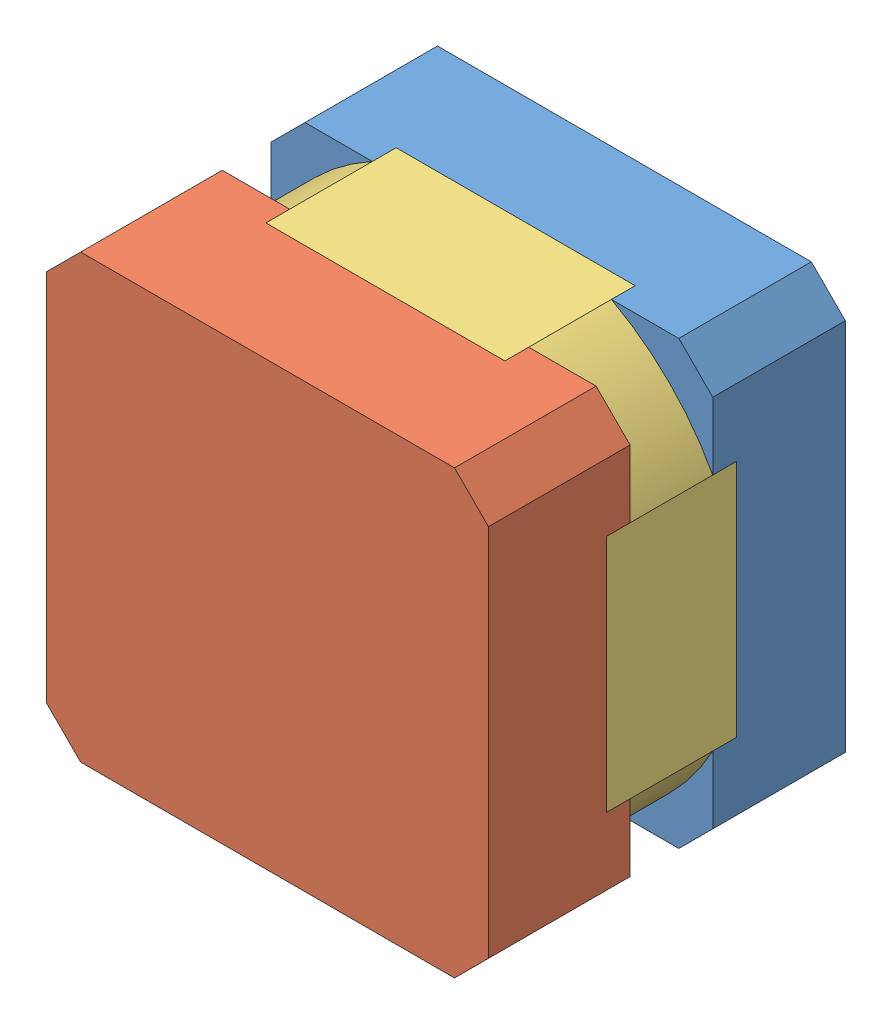
SolidWorks assembly Motor NEMA 16, configuration Valor predeterminado. Lengths in mm.
Overall size (39 39 47.5).
4 component instances, 4 part files, 12 mates.
Components (placement in the parent):
- Flange Dianteira^Motor NEMA 16-1: Flange Dianteira^Motor NEMA 16 [Valor predeterminado] at origin size (39 39 11.7) (virtual)
- Flange Traseira^Motor NEMA 16-1: Flange Traseira^Motor NEMA 16 [Valor predeterminado] at (0 0 31.5) x (-1 0 0) z (0 0 -1) size (39 39 12.5) (virtual)
- Núcleo^Motor NEMA 16-2: Núcleo^Motor NEMA 16 [Valor predeterminado] at (0 0 21.1) x (-1 0 0) z (0 0 -1) size (39 39 11.5) (virtual)
- Peça3^Motor NEMA 16-1: Peça3^Motor NEMA 16 [Valor predeterminado] at (93.2899 3.2981 -16) x (-0.956559 0.291538 0) z (0 0 1) size (5 5 16) (virtual)
Mates (geometry in assembly coordinates):
- No local1: in place: plane of Flange Dianteira^Motor NEMA 16-1 through (0 0 0) normal (0 0 1); moOrthogonalPlaneRef_w of Flange Dianteira^Motor NEMA 16-1 through (0 0 0) normal (0 1 0); plane of Flange Dianteira^Motor NEMA 16-1 through (0 0 0) normal (1 0 0); unknown of Flange Dianteira^Motor NEMA 16-1
- Coincidente1: coincident aligned: plane of Flange Dianteira^Motor NEMA 16-1; plane of assembly
- Coincidente2: coincident aligned: plane of Flange Dianteira^Motor NEMA 16-1 through (0 0 0) normal (0 1 0); moOrthogonalPlaneRef_w of assembly
- Coincidente3: coincident anti-aligned: plane of Flange Dianteira^Motor NEMA 16-1 through (0 0 0) normal (1 0 0); moOrthogonalPlaneRef_w of assembly
- Coincidente7: coincident anti-aligned: plane of Flange Dianteira^Motor NEMA 16-1 through (19.5 19.5 9.6) normal (0 0 1); plane of Núcleo^Motor NEMA 16-2 through (19.5 19.5 9.6) normal (0 0 -1)
- Concêntrico1: concentric aligned: cylinder of Flange Dianteira^Motor NEMA 16-1 through (19.5 19.5 9.6) axis (0 0 1) radius 22.171; cylinder of Núcleo^Motor NEMA 16-2 through (19.5 19.5 9.6) axis (0 0 1) radius 22.171
- Concêntrico2: concentric anti-aligned: cylinder of Flange Traseira^Motor NEMA 16-1 through (19.5 19.5 21.1) axis (0 0 -1) radius 22.171; cylinder of Núcleo^Motor NEMA 16-2 through (19.5 19.5 9.6) axis (0 0 1) radius 22.171
- Coincidente8: coincident anti-aligned: plane of Flange Traseira^Motor NEMA 16-1 through (19.5 19.5 21.1) normal (0 0 -1); plane of Núcleo^Motor NEMA 16-2 through (19.5 19.5 21.1) normal (0 0 1)
- Coincidente9: coincident aligned: plane of Flange Traseira^Motor NEMA 16-1 through (39 36 19) normal (1 0 0); plane of Núcleo^Motor NEMA 16-2 through (39 30.05 9.6) normal (1 0 0)
- Coincidente10: coincident aligned: plane of Flange Dianteira^Motor NEMA 16-1 through (3 39 11.7) normal (0 1 0); plane of Núcleo^Motor NEMA 16-2 through (8.95 39 9.6) normal (0 1 0)
- Concentric2: concentric anti-aligned: circle of Flange Traseira^Motor NEMA 16-1; circle of Peça3^Motor NEMA 16-1
- Coincident1: coincident anti-aligned: plane of Flange Dianteira^Motor NEMA 16-1 through (0 39 0) normal (0 0 -1); plane of Peça3^Motor NEMA 16-1 through (19.5 19.5 0) normal (0 0 1)
